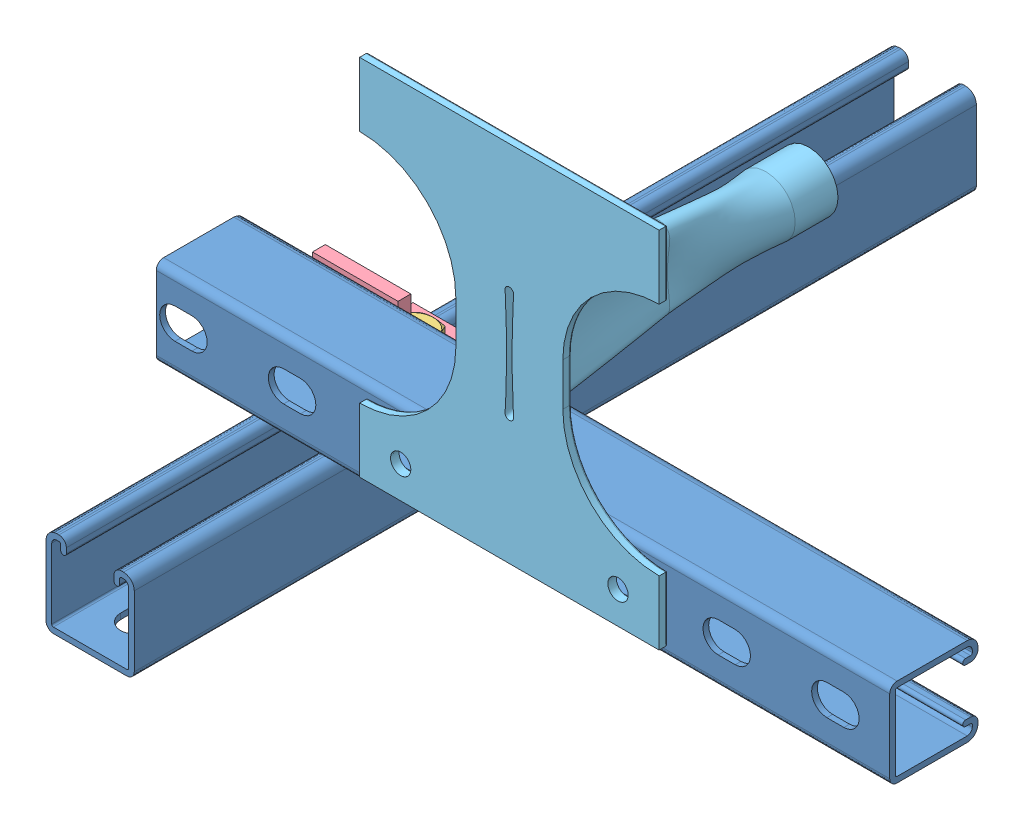
SolidWorks assembly Cooling System, configuration Default. Lengths in mm.
Overall size (342.9 226.38 393.7).
10 component instances, 5 part files, 15 mates.
Components (placement in the parent):
- P1000T - Unistrut Channel (Slots)-1: P1000T - Unistrut Channel (Slots) [1'-3.5"] at (-1704.3231 -536.1822 -102.9002) size (41.28 41.27 393.7)
- P1000T - Unistrut Channel (Slots)-2: P1000T - Unistrut Channel (Slots) [1'-1.5"] at (-1413.0633 -485.4354 -206.0876) x (0 -1 0) z (1 0 0) size (41.28 41.27 342.9)
- Channel Nut-1: Channel Nut [P2223] at (-1704.2133 -519.9042 -253.725) x (1 0 0) z (0 1 0) size (34.99 19.63 34.65)
  - P3013 - Channel Nut-3: P3013 - Channel Nut [.5"] at origin size (34.99 19.63 9.53)
  - hex bolt_ai-1: hex bolt_ai [HBOLT 0.5000-13x1x1-N] at (0 0 19.555) x (0 0 -1) z (0 -1 0) size (34.65 22 19.05)
- Channel Nut-2: Channel Nut [P2223] at (-1704.2133 -485.5448 -222.3656) x (0 -1 0) z (0 0 -1) size (34.99 19.63 34.65)
  - P3013 - Channel Nut-3: P3013 - Channel Nut [.5"] at origin size (34.99 19.63 9.53)
  - hex bolt_ai-1: hex bolt_ai [HBOLT 0.5000-13x1x1-N] at (0 0 19.555) x (0 0 -1) z (0 -1 0) size (34.65 22 19.05)
- P1026 - Unistrut 2-Hole 90 deg Fitting-1: P1026 - Unistrut 2-Hole 90 deg Fitting [Default] at (-1684.2133 -515.5448 -273.725) x (0 1 0) z (1 0 0) size (50 47 40)
- Cooling Block-1: Cooling Block [Default] at (-1586.8946 -415.4354 -181.4502) x (0 1 0) z (0 0 1) size (170 140 140.01)
Mates (geometry in assembly coordinates):
- Coincident1: coincident: plane of P1000T - Unistrut Channel (Slots)-1 through (-1693.2104 -521.3488 -496.6002) normal (-1 0 0); plane of Channel Nut-1/P3013 - Channel Nut-3 through (-1693.2104 -521.6336 -244.199) normal (1 0 0)
- Tangent1: tangent: cylinder of P1000T - Unistrut Channel (Slots)-1 through (-1691.8769 -521.3488 -496.6002) axis (0 0 1) radius 1.3335; plane of Channel Nut-1/P3013 - Channel Nut-3 through (-1690.8402 -522.6823 -244.199) normal (0 1 0)
- Coincident2: coincident: plane of P1000T - Unistrut Channel (Slots)-2 through (-1755.9633 -474.3227 -220.921) normal (0 -1 0); plane of Channel Nut-2/P3013 - Channel Nut-3 through (-1694.6883 -474.3227 -222.3656) normal (0 1 0)
- Tangent2: tangent: cylinder of P1000T - Unistrut Channel (Slots)-2 through (-1755.9633 -472.9892 -220.921) axis (1 0 0) radius 1.3335; plane of Channel Nut-2/P3013 - Channel Nut-3 through (-1694.6883 -473.5179 -219.5875) normal (0 0 -1)
- Concentric1: concentric: cylinder of Channel Nut-1/hex bolt_ai-1 through (-1704.2133 -500.3492 -253.725) axis (0 1 0) radius 6.35; cylinder of P1026 - Unistrut 2-Hole 90 deg Fitting-1 through (-1704.2133 -515.5448 -253.725) axis (0 -1 0) radius 7
- Parallel1: parallel: plane of P1000T - Unistrut Channel (Slots)-1 through (-1683.6854 -520.5931 -496.6002) normal (1 0 0); plane of P1026 - Unistrut 2-Hole 90 deg Fitting-1 through (-1684.2133 -515.5448 -273.725) normal (1 0 0)
- Coincident4: coincident: plane of P1000T - Unistrut Channel (Slots)-1 through (-1689.7496 -515.5448 -496.6002) normal (0 1 0); plane of P1026 - Unistrut 2-Hole 90 deg Fitting-1 through (-1724.2133 -515.5448 -226.725) normal (0 -1 0)
- Concentric2: concentric: cylinder of Channel Nut-2/hex bolt_ai-1 through (-1704.2133 -485.5448 -241.9206) axis (0 0 -1) radius 6.35; cylinder of P1026 - Unistrut 2-Hole 90 deg Fitting-1 through (-1704.2133 -485.5448 -232.725) axis (0 0 -1) radius 7
- Coincident5: coincident: plane of P1000T - Unistrut Channel (Slots)-2 through (-1755.9633 -470.862 -226.725) normal (0 0 -1); plane of P1026 - Unistrut 2-Hole 90 deg Fitting-1 through (-1724.2133 -465.5448 -226.725) normal (0 0 1)
- Parallel2: parallel: plane of P1000T - Unistrut Channel (Slots)-1 through (-1689.7496 -515.5448 -496.6002) normal (0 1 0); plane of P1000T - Unistrut Channel (Slots)-2 through (-1755.9633 -506.0731 -221.6767) normal (0 -1 0)
- Distance2: distance = 31.75 mm: plane of P1026 - Unistrut 2-Hole 90 deg Fitting-1 through (-1724.2133 -515.5448 -273.725) normal (-1 0 0); plane of P1000T - Unistrut Channel (Slots)-2 through (-1755.9633 -468.2585 -188.9109) normal (-1 0 0)
- Distance3: distance = 82.55 mm: plane of P1000T - Unistrut Channel (Slots)-2 through (-1755.9633 -468.2585 -185.4502) normal (0 0 1); plane of P1000T - Unistrut Channel (Slots)-1 through (-1721.5 -553.3589 -102.9002) normal (0 0 1)
- Concentric3: concentric: cylinder of Cooling Block-1 through (-1637.6946 -485.4354 -321.4512) axis (0 0 1) radius 4.7625; cylinder of P1000T - Unistrut Channel (Slots)-2 through (-1637.6946 -485.4354 -226.726) axis (0 0 1) radius 7.1437
- Parallel3: parallel: plane of P1000T - Unistrut Channel (Slots)-2 through (-1755.9633 -506.0731 -221.6767) normal (0 -1 0); plane of Cooling Block-1 through (-1664.8321 -500.4354 -185.4502) normal (0 -1 0)
- Coincident8: coincident: plane of P1000T - Unistrut Channel (Slots)-2 through (-1755.9633 -468.2585 -185.4502) normal (0 0 1); plane of Cooling Block-1 through (-1664.8321 -405.4354 -185.4502) normal (0 0 -1)
